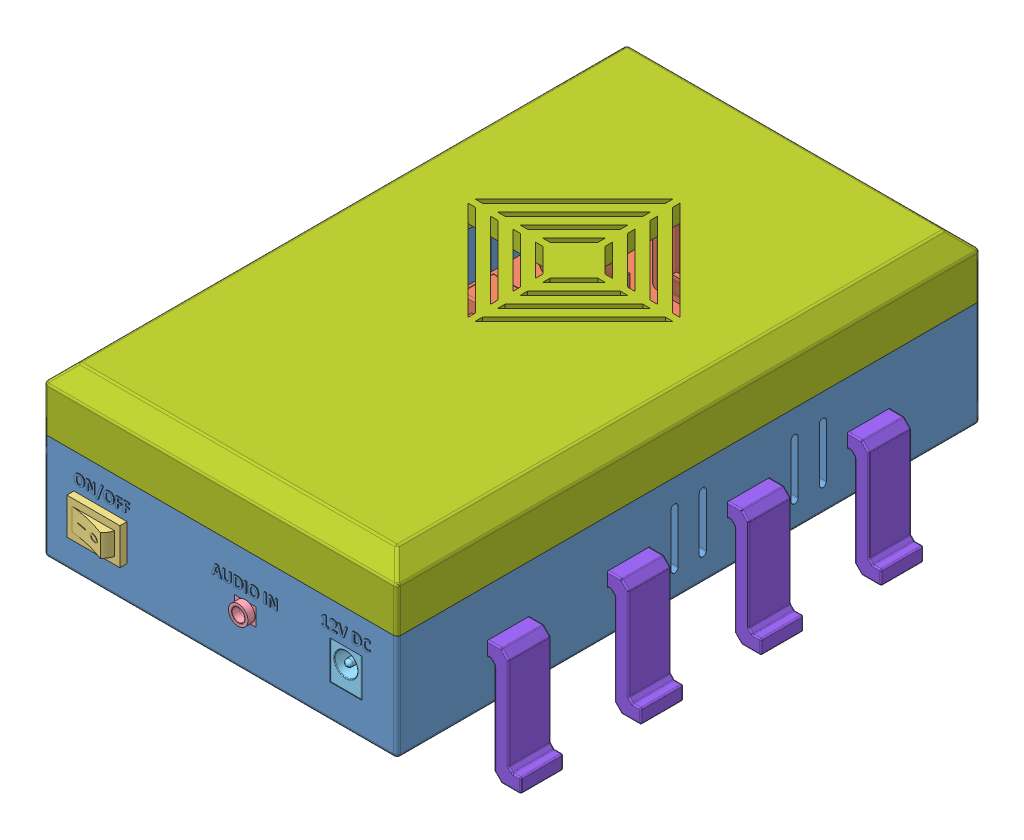
SolidWorks assembly Assembly, configuration Default. Lengths in mm.
Overall size (119 64 171.5).
19 component instances, 8 part files, 53 mates.
Components (placement in the parent):
- OPAMP_Shyamal-1: OPAMP_Shyamal [Default] at (4.6207 72.5871 193.2104) size (100 30 165.4)
- pcb-1: pcb [Default] at (95.6207 87.9986 175.4974) x (0 0 -1) z (0 1 0) size (137.29 81.92 24.42)
- power switch-1: power switch [Default] at (28.1207 82.4371 193.2104) x (0 1 0) z (1 0 0) size (10.3 12.5 15)
- female-1: female [Default] at (61.6207 87.5871 187.1604) x (0 0 -1) z (1 0 0) size (14.1 6.05 8)
- DC socket-1: DC socket [Default] at (90.1207 87.6871 193.2104) size (9.4 15 14.3)
- female-2: female [Default] at (61.6207 95.0871 34.2604) x (0 0 1) z (-1 0 0) size (14.1 6.05 8)
- pan cross head_am-2: pan cross head_am [B18.6.7M - M2 x 0.4 x 4 Type I Cross Recessed PHMS --4S] at (16.7057 89.5986 170.4974) x (0 -1 0) z (0 0 1) size (5.58 4 4)
- pan cross head_am-3: pan cross head_am [B18.6.7M - M2 x 0.4 x 4 Type I Cross Recessed PHMS --4S] at (18.7057 89.5986 43.2104) x (0 -1 0) z (0.188455 0 0.982082) size (5.58 4 4)
- pan cross head_am-4: pan cross head_am [B18.6.7M - M2 x 0.4 x 4 Type I Cross Recessed PHMS --4S] at (90.6207 89.5986 43.2104) x (0 -1 0) z (0.395734 0 0.918365) size (5.58 4 4)
- pan cross head_am-5: pan cross head_am [B18.6.7M - M2 x 0.4 x 4 Type I Cross Recessed PHMS --4S] at (90.6207 89.5986 170.4974) x (0 -1 0) z (0.6 0 0.8) size (5.58 4 4)
- Part67^Assembly-1: Part67^Assembly [Default] at (4.6207 102.5871 193.2104) x (1 0 0) z (0 1 0) size (100 165 22.5) (virtual)
- OPAMP_PIN-34: OPAMP_PIN [Default] at (6.6207 85.0871 155.7104) x (-1 0 0) z (0 0 -1) size (11.5 33 12)
- OPAMP_PIN-38: OPAMP_PIN [Default] at (6.6207 85.0871 121.7104) x (-1 0 0) z (0 0 -1) size (11.5 33 12)
- OPAMP_PIN-40: OPAMP_PIN [Default] at (6.6207 85.0871 87.7104) x (-1 0 0) z (0 0 -1) size (11.5 33 12)
- OPAMP_PIN-42: OPAMP_PIN [Default] at (6.6207 85.0871 53.7104) x (-1 0 0) z (0 0 -1) size (11.5 33 12)
- OPAMP_PIN-44: OPAMP_PIN [Default] at (102.6207 85.0871 65.7104) size (11.5 33 12)
- OPAMP_PIN-46: OPAMP_PIN [Default] at (102.6207 85.0871 99.7104) size (11.5 33 12)
- OPAMP_PIN-48: OPAMP_PIN [Default] at (102.6207 85.0871 133.7104) size (11.5 33 12)
- OPAMP_PIN-50: OPAMP_PIN [Default] at (102.6207 85.0871 167.7104) size (11.5 33 12)
Mates (geometry in assembly coordinates):
- Parallel2: parallel anti-aligned: plane of OPAMP_Shyamal-1 through (4.6207 77.5871 193.2104) normal (0 1 0); plane of pcb-1 through (95.6207 87.5871 175.4974) normal (0 -1 0)
- Parallel3: parallel aligned: plane of OPAMP_Shyamal-1 through (4.6207 102.5871 28.2104) normal (0 0 -1); plane of pcb-1 through (95.6207 87.5871 38.2104) normal (0 0 -1)
- Distance1: distance = 10 mm anti-aligned: plane of OPAMP_Shyamal-1 through (4.6207 77.5871 193.2104) normal (0 1 0); plane of pcb-1 through (95.6207 87.5871 175.4974) normal (0 -1 0)
- Distance2: distance = 5 mm anti-aligned: plane of OPAMP_Shyamal-1 through (99.6207 -106.6474 33.2104) normal (0 0 1); plane of pcb-1 through (95.6207 87.5871 38.2104) normal (0 0 -1)
- Distance3: distance = 4 mm anti-aligned: plane of pcb-1 through (95.6207 87.5871 175.4974) normal (1 0 0); plane of OPAMP_Shyamal-1 through (99.6207 -106.6474 188.2104) normal (-1 0 0)
- Parallel4: parallel: plane of OPAMP_Shyamal-1 through (4.6207 102.5871 193.2104) normal (0 0 1); line of power switch-1 through (26.6207 83.9371 185.2104) axis (-1 0 0)
- Coincident8: coincident anti-aligned: plane of OPAMP_Shyamal-1 through (4.6207 102.5871 193.2104) normal (0 0 1); plane of power switch-1 through (28.1207 82.4371 193.2104) normal (0 0 -1)
- Coincident9: coincident anti-aligned: plane of OPAMP_Shyamal-1 through (14.6207 91.2371 174.1644) normal (1 0 0); plane of power switch-1 through (14.6207 83.9371 185.2104) normal (-1 0 0)
- Coincident10: coincident anti-aligned: plane of OPAMP_Shyamal-1 through (14.6207 91.2371 174.1644) normal (0 -1 0); plane of power switch-1 through (14.6207 91.2371 185.2104) normal (0 1 0)
- Coincident13: coincident anti-aligned: plane of OPAMP_Shyamal-1 through (64.6207 90.0871 180.4001) normal (-1 0 0); plane of female-1 through (64.6207 90.0871 181.1104) normal (1 0 0)
- Coincident14: coincident anti-aligned: plane of OPAMP_Shyamal-1 through (58.6207 90.0871 180.4001) normal (0 -1 0); plane of female-1 through (61.6207 90.0871 187.1604) normal (0 1 0)
- Coincident15: coincident aligned: plane of OPAMP_Shyamal-1 through (4.6207 102.5871 193.2104) normal (0 0 1); plane of female-1 through (58.6207 90.0871 193.2104) normal (0 0 1)
- Coincident16: coincident anti-aligned: plane of OPAMP_Shyamal-1 through (85.6207 92.9871 174.1519) normal (1 0 0); plane of DC socket-1 through (85.6207 93.1871 189.9104) normal (-1 0 0)
- Coincident17: coincident anti-aligned: plane of OPAMP_Shyamal-1 through (85.6207 82.1871 174.1519) normal (0 1 0); plane of DC socket-1 through (85.6207 82.1871 189.9104) normal (0 -1 0)
- Coincident18: coincident aligned: plane of OPAMP_Shyamal-1 through (4.6207 102.5871 193.2104) normal (0 0 1); plane of DC socket-1 through (90.1207 87.6871 193.2104) normal (0 0 1)
- Coincident19: coincident anti-aligned: plane of OPAMP_Shyamal-1 through (64.6207 97.5871 41.0206) normal (-1 0 0); plane of female-2 through (64.6207 97.5871 40.3104) normal (1 0 0)
- Coincident20: coincident anti-aligned: plane of OPAMP_Shyamal-1 through (64.6207 97.5871 41.0206) normal (0 -1 0); plane of female-2 through (61.6207 97.5871 34.2604) normal (0 1 0)
- Coincident22: coincident aligned: plane of OPAMP_Shyamal-1 through (4.6207 102.5871 28.2104) normal (0 0 -1); plane of female-2 through (64.6207 97.5871 28.2104) normal (0 0 -1)
- Coincident23: coincident anti-aligned: plane of pcb-1 through (95.6207 87.9986 175.4974) normal (0 1 0); plane of pan cross head_am-2 through (17.7057 87.9986 170.4974) normal (0 -1 0)
- Concentric1: concentric aligned: circle of pcb-1; circle of pan cross head_am-2
- Coincident25: coincident anti-aligned: plane of pcb-1 through (95.6207 87.9986 175.4974) normal (0 1 0); plane of pan cross head_am-3 through (19.6878 87.9986 43.0219) normal (0 -1 0)
- Concentric2: concentric aligned: circle of pcb-1; circle of pan cross head_am-3
- Coincident26: coincident anti-aligned: plane of pcb-1 through (95.6207 87.9986 175.4974) normal (0 1 0); plane of pan cross head_am-4 through (91.5391 87.9986 42.8146) normal (0 -1 0)
- Concentric3: concentric aligned: circle of pcb-1; circle of pan cross head_am-4
- Coincident27: coincident anti-aligned: plane of pcb-1 through (95.6207 87.9986 175.4974) normal (0 1 0); plane of pan cross head_am-5 through (91.4207 87.9986 169.8974) normal (0 -1 0)
- Concentric4: concentric aligned: circle of pcb-1; circle of pan cross head_am-5
- Concentric5: concentric anti-aligned: cylinder of OPAMP_Shyamal-1 through (104.6207 87.0871 161.7104) axis (-1 0 0) radius 1; cylinder of OPAMP_PIN-34 through (2.6207 87.0871 161.7104) axis (1 0 0) radius 1
- Coincident36: coincident anti-aligned: plane of OPAMP_Shyamal-1 through (6.6207 85.0871 155.7104) normal (0 1 0); plane of OPAMP_PIN-34 through (-1.3793 85.0871 155.7104) normal (0 -1 0)
- Coincident37: coincident anti-aligned: plane of OPAMP_Shyamal-1 through (6.6207 72.5871 193.2104) normal (-1 0 0); plane of OPAMP_PIN-34 through (6.6207 85.0871 155.7104) normal (1 0 0)
- Concentric6: concentric anti-aligned: cylinder of OPAMP_Shyamal-1 through (104.6207 87.0871 127.7104) axis (-1 0 0) radius 1; cylinder of OPAMP_PIN-38 through (2.6207 87.0871 127.7104) axis (1 0 0) radius 1
- Coincident38: coincident anti-aligned: plane of OPAMP_Shyamal-1 through (6.6207 85.0871 121.7104) normal (0 1 0); plane of OPAMP_PIN-38 through (-1.3793 85.0871 121.7104) normal (0 -1 0)
- Coincident39: coincident anti-aligned: plane of OPAMP_Shyamal-1 through (6.6207 72.5871 193.2104) normal (-1 0 0); plane of OPAMP_PIN-38 through (6.6207 85.0871 121.7104) normal (1 0 0)
- Concentric7: concentric anti-aligned: cylinder of OPAMP_Shyamal-1 through (104.6207 87.0871 93.7104) axis (-1 0 0) radius 1; cylinder of OPAMP_PIN-40 through (2.6207 87.0871 93.7104) axis (1 0 0) radius 1
- Coincident40: coincident anti-aligned: plane of OPAMP_Shyamal-1 through (6.6207 85.0871 87.7104) normal (0 1 0); plane of OPAMP_PIN-40 through (-1.3793 85.0871 87.7104) normal (0 -1 0)
- Coincident41: coincident anti-aligned: plane of OPAMP_Shyamal-1 through (6.6207 72.5871 193.2104) normal (-1 0 0); plane of OPAMP_PIN-40 through (6.6207 85.0871 87.7104) normal (1 0 0)
- Concentric8: concentric anti-aligned: cylinder of OPAMP_Shyamal-1 through (104.6207 87.0871 59.7104) axis (-1 0 0) radius 1; cylinder of OPAMP_PIN-42 through (2.6207 87.0871 59.7104) axis (1 0 0) radius 1
- Coincident42: coincident anti-aligned: plane of OPAMP_Shyamal-1 through (6.6207 85.0871 53.7104) normal (0 1 0); plane of OPAMP_PIN-42 through (-1.3793 85.0871 53.7104) normal (0 -1 0)
- Coincident43: coincident anti-aligned: plane of OPAMP_Shyamal-1 through (6.6207 72.5871 193.2104) normal (-1 0 0); plane of OPAMP_PIN-42 through (6.6207 85.0871 53.7104) normal (1 0 0)
- Concentric9: concentric aligned: cylinder of OPAMP_Shyamal-1 through (104.6207 87.0871 59.7104) axis (-1 0 0) radius 1; cylinder of OPAMP_PIN-44 through (106.6207 87.0871 59.7104) axis (-1 0 0) radius 1
- Coincident44: coincident anti-aligned: plane of OPAMP_Shyamal-1 through (102.6207 85.0871 53.7104) normal (0 1 0); plane of OPAMP_PIN-44 through (110.6207 85.0871 65.7104) normal (0 -1 0)
- Coincident45: coincident anti-aligned: plane of OPAMP_Shyamal-1 through (102.6207 72.5871 193.2104) normal (1 0 0); plane of OPAMP_PIN-44 through (102.6207 85.0871 65.7104) normal (-1 0 0)
- Concentric10: concentric aligned: cylinder of OPAMP_Shyamal-1 through (104.6207 87.0871 93.7104) axis (-1 0 0) radius 1; cylinder of OPAMP_PIN-46 through (106.6207 87.0871 93.7104) axis (-1 0 0) radius 1
- Coincident46: coincident anti-aligned: plane of OPAMP_Shyamal-1 through (102.6207 85.0871 87.7104) normal (0 1 0); plane of OPAMP_PIN-46 through (110.6207 85.0871 99.7104) normal (0 -1 0)
- Coincident47: coincident anti-aligned: plane of OPAMP_Shyamal-1 through (102.6207 72.5871 193.2104) normal (1 0 0); plane of OPAMP_PIN-46 through (102.6207 85.0871 99.7104) normal (-1 0 0)
- Concentric11: concentric aligned: cylinder of OPAMP_Shyamal-1 through (104.6207 87.0871 127.7104) axis (-1 0 0) radius 1; cylinder of OPAMP_PIN-48 through (106.6207 87.0871 127.7104) axis (-1 0 0) radius 1
- Coincident48: coincident anti-aligned: plane of OPAMP_Shyamal-1 through (102.6207 85.0871 121.7104) normal (0 1 0); plane of OPAMP_PIN-48 through (110.6207 85.0871 133.7104) normal (0 -1 0)
- Coincident49: coincident anti-aligned: plane of OPAMP_Shyamal-1 through (102.6207 72.5871 193.2104) normal (1 0 0); plane of OPAMP_PIN-48 through (102.6207 85.0871 133.7104) normal (-1 0 0)
- Concentric12: concentric aligned: cylinder of OPAMP_Shyamal-1 through (104.6207 87.0871 161.7104) axis (-1 0 0) radius 1; cylinder of OPAMP_PIN-50 through (106.6207 87.0871 161.7104) axis (-1 0 0) radius 1
- Coincident50: coincident anti-aligned: plane of OPAMP_Shyamal-1 through (102.6207 85.0871 155.7104) normal (0 1 0); plane of OPAMP_PIN-50 through (110.6207 85.0871 167.7104) normal (0 -1 0)
- Coincident51: coincident anti-aligned: plane of OPAMP_Shyamal-1 through (102.6207 72.5871 193.2104) normal (1 0 0); plane of OPAMP_PIN-50 through (102.6207 85.0871 167.7104) normal (-1 0 0)
- Coincident52: coincident anti-aligned: plane of OPAMP_Shyamal-1 through (4.6207 102.5871 193.2104) normal (0 1 0); plane of Part67^Assembly-1 through (4.6207 102.5871 193.2104) normal (0 -1 0)
- Coincident53: coincident aligned: plane of OPAMP_Shyamal-1 through (4.6207 102.5871 193.2104) normal (-1 0 0); plane of Part67^Assembly-1 through (4.6207 115.0871 28.2104) normal (-1 0 0)
- Coincident54: coincident aligned: plane of OPAMP_Shyamal-1 through (4.6207 102.5871 193.2104) normal (0 0 1); plane of Part67^Assembly-1 through (4.6207 115.0871 193.2104) normal (0 0 1)
